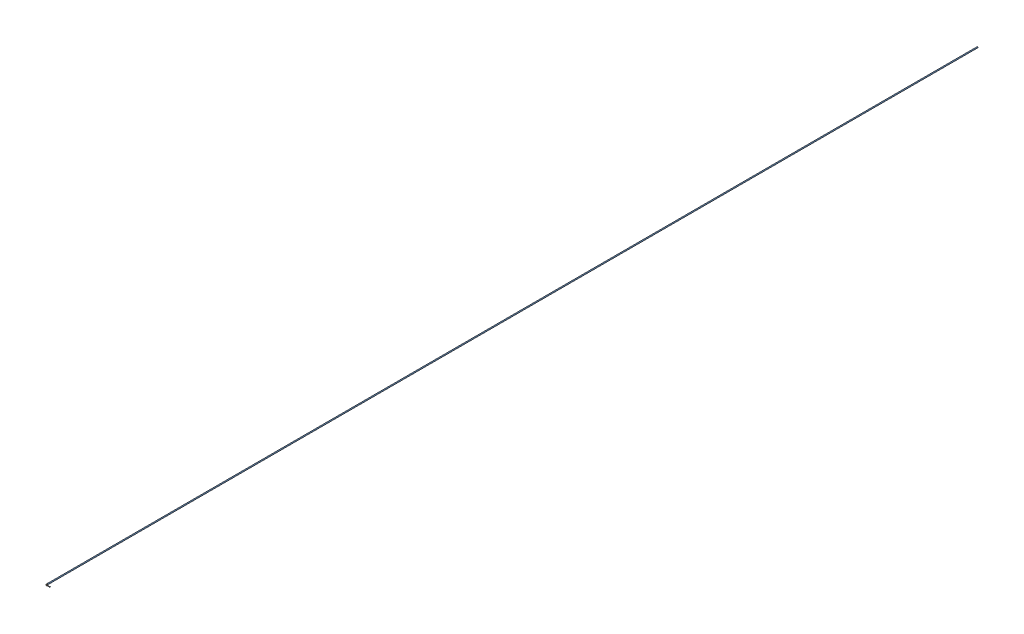
SolidWorks assembly main assembly, configuration Default. Lengths in mm.
Overall size (2349.47 593.54 500753).
8 component instances, 6 part files, 7 mates.
Components (placement in the parent):
- 500 mm pipe-1: 500 mm pipe [Default] at (-52900.421 -64298.5133 -428704.6828) size (502 502 500000)
- diameter change to 200-1: diameter change to 200 [Default] at (-52425.5556 -64597.6918 71797.3172) x (0.995147 -0.0984 0) z (0 0 1) size (202 502 502)
- turn-pipe 500-1: turn-pipe 500 [Default] at (-52400.8573 -64347.9099 71797.3172) x (0 0 -1) z (0.0984 0.995147 0) size (753 753 502)
- 200 mm pipe diameter-1: 200 mm pipe diameter [Default] at (-52209.7759 -64468.2965 71797.3172) x (0.995147 -0.0984 0) z (0 0 1) size (250 202 202)
- 200 mm pipe diameter-2: 200 mm pipe diameter [Default] at (-51960.9892 -64492.8964 71797.3172) x (0.995147 -0.0984 0) z (0 0 1) size (250 202 202)
- angle for 200 mm-1: angle for 200 mm [Default] at (-51702.2641 -64416.9865 71797.3172) x (0.995147 -0.0984 0) z (0.098315 0.994296 0.041358) size (228.51 230.11 202)
- 200 mm pipe diameter-3: 200 mm pipe diameter [Default] at (-51517.0142 -64535.3448 71764.5415) x (0.936524 -0.078389 -0.341728) z (0.341728 -0.013833 0.939697) size (250 202 202)
- 3 part 200 diam.-1: 3 part 200 diam. [Default] at (-50831.1571 -64475.7881 71728.4111) x (-0.345996 -0.04915 -0.936948) z (0.05665 0.995711 -0.073153) size (301 400 202)
Mates (geometry in assembly coordinates):
- Coincident5: coincident anti-aligned: circle of 500 mm pipe-1; circle of turn-pipe 500-1
- Coincident6: coincident aligned: circle of diameter change to 200-1; circle of turn-pipe 500-1
- Coincident8: coincident aligned: circle of diameter change to 200-1; circle of 200 mm pipe diameter-1
- Coincident9: coincident aligned: circle of 200 mm pipe diameter-1; circle of 200 mm pipe diameter-2
- Coincident10: coincident anti-aligned: circle of 200 mm pipe diameter-2; circle of angle for 200 mm-1
- Coincident11: coincident anti-aligned: circle of angle for 200 mm-1; circle of 200 mm pipe diameter-3
- Coincident12: coincident aligned: circle of 200 mm pipe diameter-3; circle of 3 part 200 diam.-1
